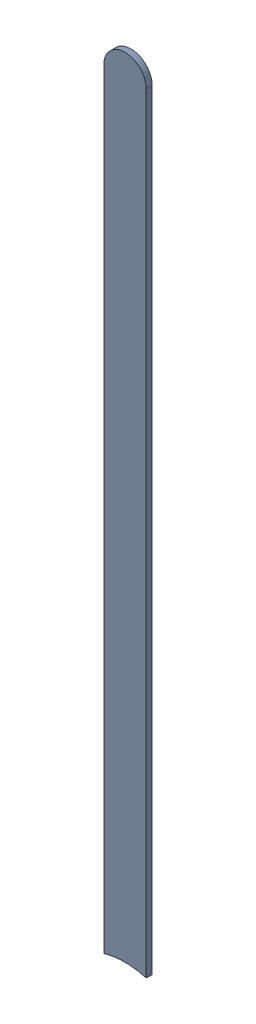
SolidWorks assembly Track (20.574mm,48.387mm)(20.574mm,53.426mm) on Bottom Layer, configuration Predeterminado. Lengths in mm.
Overall size (0.25 4.73 0.04).
2 component instances, 1 part files, 0 mates.
Components (placement in the parent):
- Track (20.574mm,48.387mm)(20.574mm,53.426mm) on Bottom Layer-1-1: Track (20.574mm,48.387mm)(20.574mm,53.426mm) on Bottom Layer-1 [Predeterminado] at (-68.317 -44.187 -0.4013) size (0.25 4.73 0.04)
  - Track (20.574mm,48.387mm)(20.574mm,53.426mm) on Bottom Layer-Part-1-1: Track (20.574mm,48.387mm)(20.574mm,53.426mm) on Bottom Layer-Part-1 [Predeterminado] at origin size (0.25 4.73 0.04)
